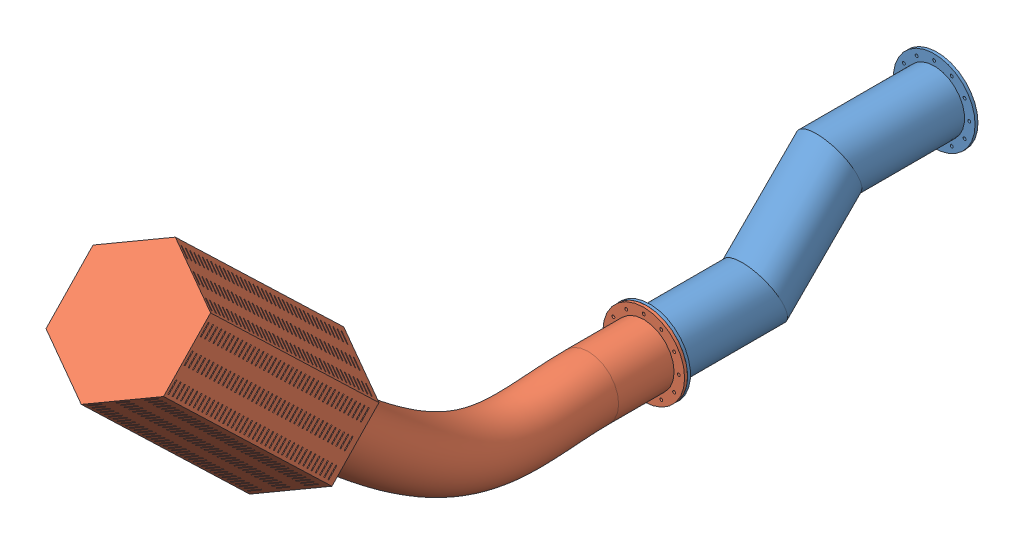
SolidWorks assembly Assem1, configuration Default. Lengths in mm.
Overall size (201.24 645.01 1465.39).
2 component instances, 2 part files, 3 mates.
Components (placement in the parent):
- Part1-1: Part1 [Default] at (95.9527 113.8167 528.0013) size (140 267.28 497.28)
- Part2-1: Part2 [Default] at (95.9527 113.8167 533.0013) size (201.24 645.01 968.12)
Mates (geometry in assembly coordinates):
- Concentric1: concentric: cylinder of Part1-1 through (95.9527 113.8167 533.0013) axis (0 0 -1) radius 70; cylinder of Part2-1 through (95.9527 113.8167 538.0013) axis (0 0 -1) radius 70
- Coincident1: coincident: plane of Part1-1 through (95.9527 113.8167 533.0013) normal (0 0 1); plane of Part2-1 through (95.9527 113.8167 533.0013) normal (0 0 -1)
- Concentric2: concentric: cylinder of Part1-1 through (147.9142 143.8167 533.0013) axis (0 0 -1) radius 2.5; cylinder of Part2-1 through (147.9142 143.8167 538.0013) axis (0 0 -1) radius 2.5
